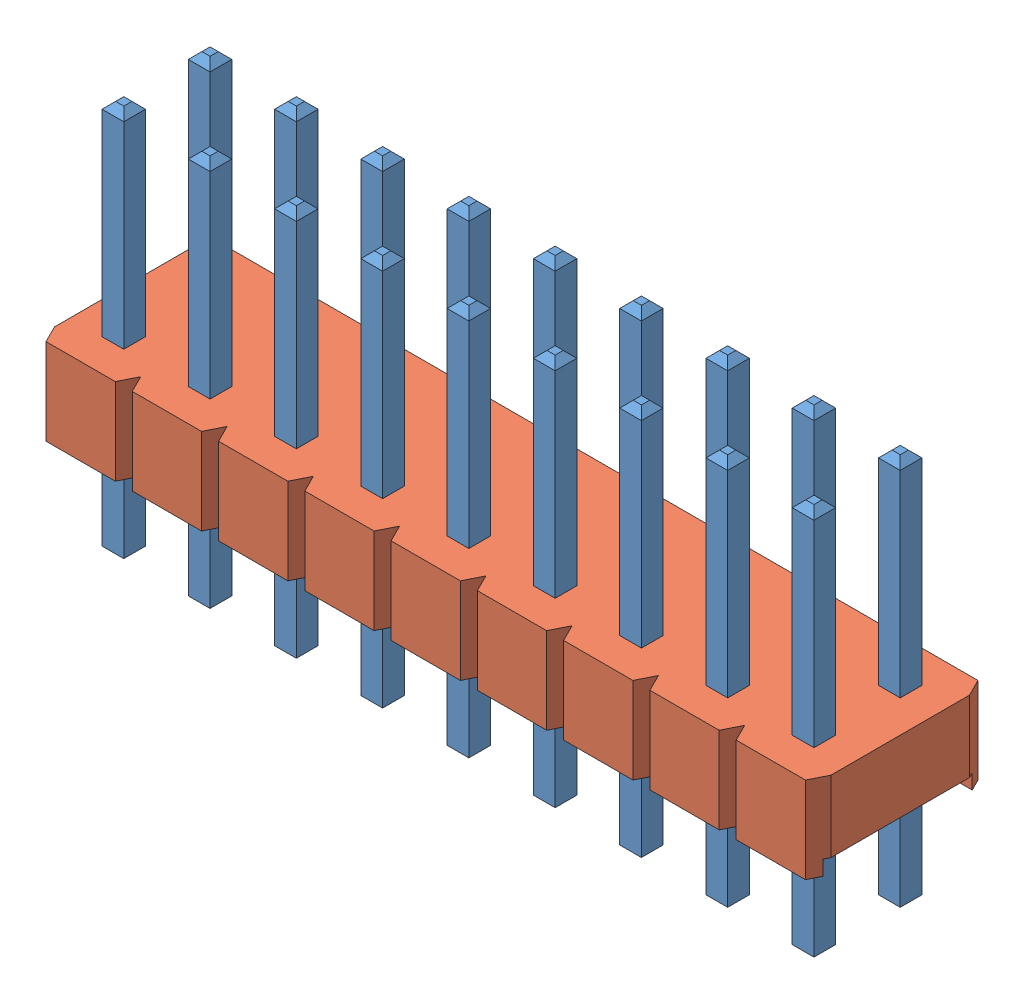
SolidWorks assembly 61301821121_Download_IGS_61301821121_rev1, configuration Default. Lengths in mm.
Overall size (22.86 11.54 5.08).
20 component instances, 2 part files, 0 mates.
Components (placement in the parent):
- DEFAULT-1: DEFAULT [Predeterminado] at origin size (22.86 11.54 5.08)
  - DEFAULT-1: DEFAULT [Predeterminado] at (-10.16 1.5 0) x (1 0 0) z (0 -1 0) size (0.64 0.64 11.54)
  - DEFAULT-2: DEFAULT [Predeterminado] at (-10.16 1.5 -2.54) x (1 0 0) z (0 -1 0) size (0.64 0.64 11.54)
  - DEFAULT-3: DEFAULT [Predeterminado] at (-7.62 1.5 0) x (1 0 0) z (0 -1 0) size (0.64 0.64 11.54)
  - DEFAULT-4: DEFAULT [Predeterminado] at (-7.62 1.5 -2.54) x (1 0 0) z (0 -1 0) size (0.64 0.64 11.54)
  - DEFAULT-5: DEFAULT [Predeterminado] at (-5.08 1.5 0) x (1 0 0) z (0 -1 0) size (0.64 0.64 11.54)
  - DEFAULT-6: DEFAULT [Predeterminado] at (-5.08 1.5 -2.54) x (1 0 0) z (0 -1 0) size (0.64 0.64 11.54)
  - DEFAULT-7: DEFAULT [Predeterminado] at (-2.54 1.5 0) x (1 0 0) z (0 -1 0) size (0.64 0.64 11.54)
  - DEFAULT-8: DEFAULT [Predeterminado] at (-2.54 1.5 -2.54) x (1 0 0) z (0 -1 0) size (0.64 0.64 11.54)
  - DEFAULT-9: DEFAULT [Predeterminado] at (0 1.5 0) x (1 0 0) z (0 -1 0) size (0.64 0.64 11.54)
  - DEFAULT-10: DEFAULT [Predeterminado] at (0 1.5 -2.54) x (1 0 0) z (0 -1 0) size (0.64 0.64 11.54)
  - DEFAULT-11: DEFAULT [Predeterminado] at (2.54 1.5 0) x (1 0 0) z (0 -1 0) size (0.64 0.64 11.54)
  - DEFAULT-12: DEFAULT [Predeterminado] at (2.54 1.5 -2.54) x (1 0 0) z (0 -1 0) size (0.64 0.64 11.54)
  - DEFAULT-13: DEFAULT [Predeterminado] at (5.08 1.5 0) x (1 0 0) z (0 -1 0) size (0.64 0.64 11.54)
  - DEFAULT-14: DEFAULT [Predeterminado] at (5.08 1.5 -2.54) x (1 0 0) z (0 -1 0) size (0.64 0.64 11.54)
  - DEFAULT-15: DEFAULT [Predeterminado] at (7.62 1.5 0) x (1 0 0) z (0 -1 0) size (0.64 0.64 11.54)
  - DEFAULT-16: DEFAULT [Predeterminado] at (7.62 1.5 -2.54) x (1 0 0) z (0 -1 0) size (0.64 0.64 11.54)
  - DEFAULT-17: DEFAULT [Predeterminado] at (10.16 1.5 0) x (1 0 0) z (0 -1 0) size (0.64 0.64 11.54)
  - DEFAULT-18: DEFAULT [Predeterminado] at (10.16 1.5 -2.54) x (1 0 0) z (0 -1 0) size (0.64 0.64 11.54)
  - DEFAULT-1-1: DEFAULT-1 [Predeterminado] at origin size (22.86 2.54 5.08)
